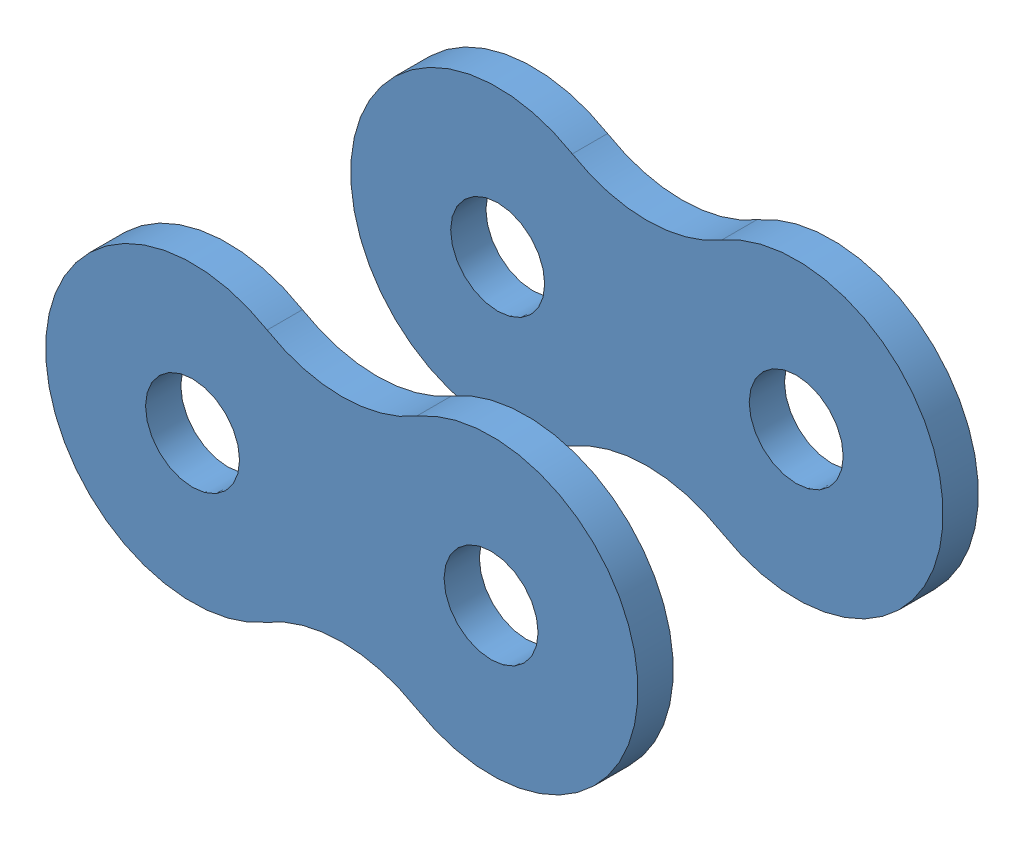
SolidWorks assembly Assem1, configuration Default. Lengths in mm.
Overall size (50.46 25.06 29.02).
3 component instances, 1 part files, 0 mates.
Components (placement in the parent):
- plates linkage-1: plates linkage [Default] at (5.2594 2.7559 -17.6168) size (50.46 25.06 29.02)
  - plates-1: plates [Default] at (6.3437 27.0699 36.5425) size (50.4 25 3)
  - plates-2: plates [Default] at (6.4029 27.1335 62.5625) size (50.4 25 3)
